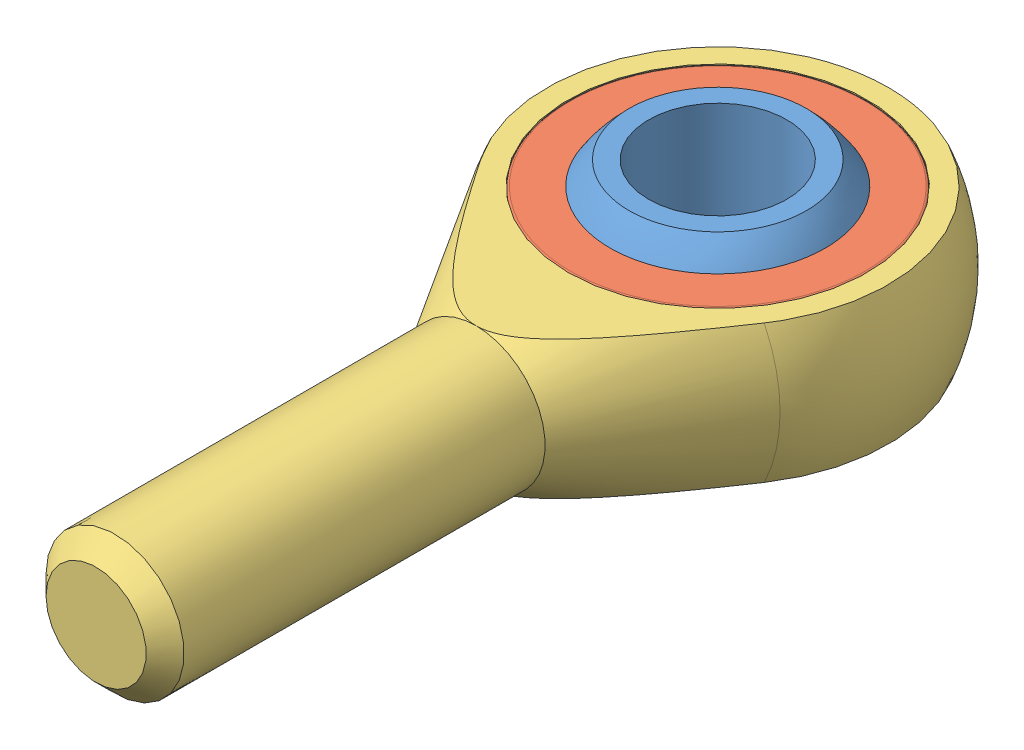
SolidWorks assembly Przegub kulowy_GN 648.2_12, configuration Domyślna. Lengths in mm.
Overall size (32 16 70).
3 component instances, 3 part files, 8 mates.
Components (placement in the parent):
- ROD-END-GN-648.2-1-12-1: ROD-END-GN-648.2-1-12 [12] x (-1 0 0) z (0 0 -1) size (22.2 16 22.2)
- ROD-END-GN-648.2-2-12-1: ROD-END-GN-648.2-2-12 [12] x (0.997964 0 0.063787) z (-0.063787 0 0.997964) size (26 12 26)
- ROD-END-GN-648.2-3-12-1: ROD-END-GN-648.2-3-12 [12] at origin size (32 12 70)
Mates (geometry in assembly coordinates):
- Koncentryczne1: concentric: sphere of ROD-END-GN-648.2-2-12-1; sphere of ROD-END-GN-648.2-1-12-1
- Limit kąta1: limit planar angle = 0 rad aligned: cylinder of ROD-END-GN-648.2-1-12-1 through (0 -11.1 0) axis (0 -1 0) radius 6
- Limit kąta2: limit planar angle = 0 rad aligned: cylinder of ROD-END-GN-648.2-2-12-1 through (0 6 0) axis (0 -1 0) radius 13
- Koncentryczne5: concentric anti-aligned: cylinder of ROD-END-GN-648.2-3-12-1 through (0 -6 0) axis (0 1 0) radius 13; cylinder of ROD-END-GN-648.2-2-12-1 through (0 6 0) axis (0 -1 0) radius 13
- Wspólnie1: coincident aligned: plane of ROD-END-GN-648.2-3-12-1 through (-16 6 21) normal (0 1 0); plane of ROD-END-GN-648.2-2-12-1 through (0 6 0) normal (0 1 0)
- Wspólnie2: coincident anti-aligned: plane of ROD-END-GN-648.2-1-12-1 through (0 0 0) normal (0 0 -1)
- Wspólnie3: coincident aligned: plane of ROD-END-GN-648.2-1-12-1 through (0 0 0) normal (0 1 0)
- Wspólnie4: coincident anti-aligned: plane of ROD-END-GN-648.2-1-12-1 through (0 0 0) normal (-1 0 0)
